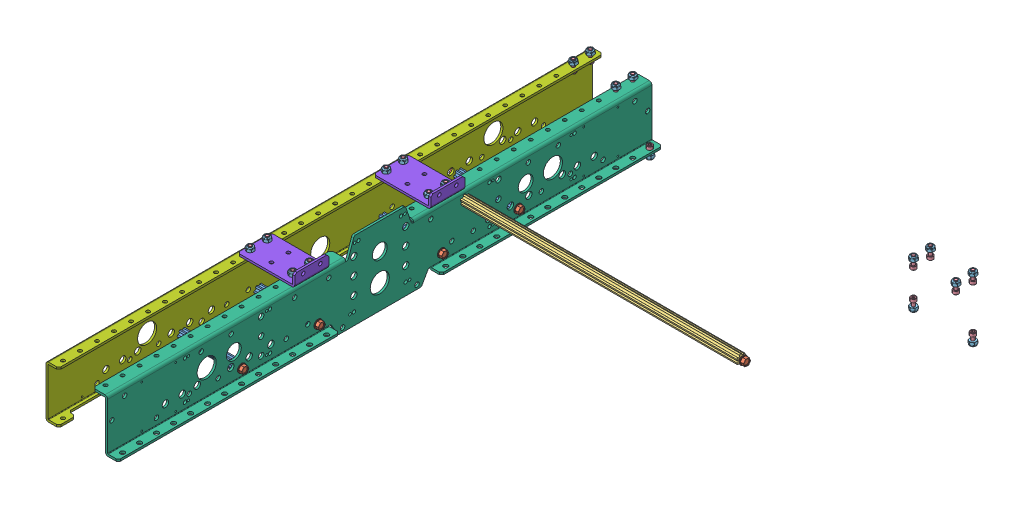
SolidWorks assembly AM14U3Long_Frame_Half, configuration Default. Lengths in mm.
Overall size (595.34 116.33 812.8).
59 component instances, 8 part files, 0 mates.
Components (placement in the parent):
- 500Churro_3.375-1: 500Churro_3.375 [Default] at (-501.65 -66.929 448.437) x (0 0 1) z (-1 0 0) size (14.66 12.7 85.72)
- 500Churro_3.375-2: 500Churro_3.375 [Default] at (-501.65 -66.929 562.737) x (0 0 1) z (-1 0 0) size (14.66 12.7 85.72)
- 500Churro_3.375-3: 500Churro_3.375 [Default] at (-501.65 -66.929 264.287) x (0 0 1) z (-1 0 0) size (14.66 12.7 85.72)
- 500Churro_3.375-4: 500Churro_3.375 [Default] at (-501.65 -66.929 149.987) x (0 0 1) z (-1 0 0) size (14.66 12.7 85.72)
- ThreadRollingScrew_0.25-20x0.75_FHTS 0.25-20-G-0.75-C-1: ThreadRollingScrew_0.25-20x0.75_FHTS 0.25-20-G-0.75-C [Default] at (-498.475 -66.929 562.737) x (-1 0 0) z (0 0.924225 0.381849) size (24.64 12.19 12.19)
- ThreadRollingScrew_0.25-20x0.75_FHTS 0.25-20-G-0.75-C-2: ThreadRollingScrew_0.25-20x0.75_FHTS 0.25-20-G-0.75-C [Default] at (-498.475 -66.929 448.437) x (-1 0 0) z (0 0.924225 0.381849) size (24.64 12.19 12.19)
- ThreadRollingScrew_0.25-20x0.75_FHTS 0.25-20-G-0.75-C-3: ThreadRollingScrew_0.25-20x0.75_FHTS 0.25-20-G-0.75-C [Default] at (-498.475 -66.929 264.287) x (-1 0 0) z (0 0.924225 0.381849) size (24.64 12.19 12.19)
- ThreadRollingScrew_0.25-20x0.75_FHTS 0.25-20-G-0.75-C-4: ThreadRollingScrew_0.25-20x0.75_FHTS 0.25-20-G-0.75-C [Default] at (-498.475 -66.929 149.987) x (-1 0 0) z (0 0.924225 0.381849) size (24.64 12.19 12.19)
- ThreadRollingScrew_0.25-20x0.75_FHTS 0.25-20-G-0.75-C-5: ThreadRollingScrew_0.25-20x0.75_FHTS 0.25-20-G-0.75-C [Default] at (-590.55 -66.929 562.737) size (24.64 12.19 12.19)
- ThreadRollingScrew_0.25-20x0.75_FHTS 0.25-20-G-0.75-C-6: ThreadRollingScrew_0.25-20x0.75_FHTS 0.25-20-G-0.75-C [Default] at (-590.55 -66.929 448.437) size (24.64 12.19 12.19)
- ThreadRollingScrew_0.25-20x0.75_FHTS 0.25-20-G-0.75-C-7: ThreadRollingScrew_0.25-20x0.75_FHTS 0.25-20-G-0.75-C [Default] at (-590.55 -66.929 149.987) size (24.64 12.19 12.19)
- ThreadRollingScrew_0.25-20x0.75_FHTS 0.25-20-G-0.75-C-8: ThreadRollingScrew_0.25-20x0.75_FHTS 0.25-20-G-0.75-C [Default] at (-590.55 -66.929 264.287) size (24.64 12.19 12.19)
- ThreadRollingScrew_0.25-20x0.75_FHTS 0.25-20-G-0.75-C-9: ThreadRollingScrew_0.25-20x0.75_FHTS 0.25-20-G-0.75-C [Default] at (-501.65 -15.494 229.362) size (24.64 12.19 12.19)
- ThreadRollingScrew_0.25-20x0.75_FHTS 0.25-20-G-0.75-C-10: ThreadRollingScrew_0.25-20x0.75_FHTS 0.25-20-G-0.75-C [Default] at (-82.55 -15.494 229.362) x (-1 0 0) z (0 -0.924225 -0.381849) size (24.64 12.19 12.19)
- 500Churro_cut_16.25-1: 500Churro_cut_16.25 [Default] at (-85.725 -15.494 229.362) x (0 0.99241 0.122972) z (-1 0 0) size (14.66 12.7 412.75)
- Screw_SHCS_10-32x0.5_HX-SHCS 0.19-32x1.375x1-C-1: Screw_SHCS_10-32x0.5_HX-SHCS 0.19-32x1.375x1-C [Default] at (-577.85 -11.43 -11.938) x (0 1 0) z (0 0 1) size (17.53 7.94 7.94)
- Screw_SHCS_10-32x0.5_HX-SHCS 0.19-32x1.375x1-C-2: Screw_SHCS_10-32x0.5_HX-SHCS 0.19-32x1.375x1-C [Default] at (-577.85 -11.43 -37.338) x (0 1 0) z (0 0 1) size (17.53 7.94 7.94)
- Screw_SHCS_10-32x0.5_HX-SHCS 0.19-32x1.375x1-C-3: Screw_SHCS_10-32x0.5_HX-SHCS 0.19-32x1.375x1-C [Default] at (-514.35 -11.43 -37.338) x (0 1 0) z (0 0 1) size (17.53 7.94 7.94)
- Screw_SHCS_10-32x0.5_HX-SHCS 0.19-32x1.375x1-C-4: Screw_SHCS_10-32x0.5_HX-SHCS 0.19-32x1.375x1-C [Default] at (-514.35 -11.43 -11.938) x (0 1 0) z (0 0 1) size (17.53 7.94 7.94)
- Screw_SHCS_10-32x0.5_HX-SHCS 0.19-32x1.375x1-C-5: Screw_SHCS_10-32x0.5_HX-SHCS 0.19-32x1.375x1-C [Default] at (-488.95 -73.152 -37.338) x (0 -1 0) z (0 0 1) size (17.53 7.94 7.94)
- Screw_SHCS_10-32x0.5_HX-SHCS 0.19-32x1.375x1-C-6: Screw_SHCS_10-32x0.5_HX-SHCS 0.19-32x1.375x1-C [Default] at (-577.85 -73.152 -37.338) x (0 -1 0) z (0 0 1) size (17.53 7.94 7.94)
- Screw_SHCS_10-32x0.5_HX-SHCS 0.19-32x1.375x1-C-7: Screw_SHCS_10-32x0.5_HX-SHCS 0.19-32x1.375x1-C [Default] at (-6.35 -11.176 -11.938) x (0 1 0) z (-0.991845 0 0.127447) size (17.53 7.94 7.94)
- Screw_SHCS_10-32x0.5_HX-SHCS 0.19-32x1.375x1-C-8: Screw_SHCS_10-32x0.5_HX-SHCS 0.19-32x1.375x1-C [Default] at (-6.35 -11.176 -37.338) x (0 1 0) z (0.595464 0 0.803382) size (17.53 7.94 7.94)
- Screw_SHCS_10-32x0.5_HX-SHCS 0.19-32x1.375x1-C-9: Screw_SHCS_10-32x0.5_HX-SHCS 0.19-32x1.375x1-C [Default] at (-69.85 -11.176 -11.938) x (0 1 0) z (0.578861 0 0.815426) size (17.53 7.94 7.94)
- Screw_SHCS_10-32x0.5_HX-SHCS 0.19-32x1.375x1-C-10: Screw_SHCS_10-32x0.5_HX-SHCS 0.19-32x1.375x1-C [Default] at (-69.85 -11.176 -37.338) x (0 1 0) z (0.958905 0 0.283727) size (17.53 7.94 7.94)
- Screw_SHCS_10-32x0.5_HX-SHCS 0.19-32x1.375x1-C-11: Screw_SHCS_10-32x0.5_HX-SHCS 0.19-32x1.375x1-C [Default] at (-6.35 -73.406 -37.338) x (0 -1 0) z (-0.989362 0 -0.145473) size (17.53 7.94 7.94)
- Screw_SHCS_10-32x0.5_HX-SHCS 0.19-32x1.375x1-C-12: Screw_SHCS_10-32x0.5_HX-SHCS 0.19-32x1.375x1-C [Default] at (-95.25 -73.406 -37.338) x (0 -1 0) z (-0.875347 0 0.483496) size (17.53 7.94 7.94)
- NylockNut_10-32-1: NylockNut_10-32 [Default] at (-69.85 0 -11.938) x (1 0 0) z (0 1 0) size (9.53 11 5.96)
- NylockNut_10-32-2: NylockNut_10-32 [Default] at (-69.85 0 -37.338) x (1 0 0) z (0 1 0) size (9.53 11 5.96)
- NylockNut_10-32-3: NylockNut_10-32 [Default] at (-6.35 0 -37.338) x (1 0 0) z (0 1 0) size (9.53 11 5.96)
- NylockNut_10-32-4: NylockNut_10-32 [Default] at (-6.35 0 -11.938) x (1 0 0) z (0 1 0) size (9.53 11 5.96)
- NylockNut_10-32-5: NylockNut_10-32 [Default] at (-6.35 -84.582 -37.338) x (1 0 0) z (0 -1 0) size (9.53 11 5.96)
- NylockNut_10-32-6: NylockNut_10-32 [Default] at (-95.25 -84.582 -37.338) x (1 0 0) z (0 -1 0) size (9.53 11 5.96)
- NylockNut_10-32-7: NylockNut_10-32 [Default] at (-514.35 0 -11.938) x (1 0 0) z (0 1 0) size (9.53 11 5.96)
- NylockNut_10-32-8: NylockNut_10-32 [Default] at (-514.35 0 -37.338) x (1 0 0) z (0 1 0) size (9.53 11 5.96)
- NylockNut_10-32-9: NylockNut_10-32 [Default] at (-577.85 0 -37.338) x (1 0 0) z (0 1 0) size (9.53 11 5.96)
- NylockNut_10-32-10: NylockNut_10-32 [Default] at (-577.85 0 -11.938) x (1 0 0) z (0 1 0) size (9.53 11 5.96)
- NylockNut_10-32-11: NylockNut_10-32 [Default] at (-488.95 -84.582 -37.338) x (1 0 0) z (0 -1 0) size (9.53 11 5.96)
- NylockNut_10-32-12: NylockNut_10-32 [Default] at (-577.85 -84.582 -37.338) x (1 0 0) z (0 -1 0) size (9.53 11 5.96)
- Screw_SHCS_10-32x0.5_HX-SHCS 0.19-32x1.375x1-C-13: Screw_SHCS_10-32x0.5_HX-SHCS 0.19-32x1.375x1-C [Default] at (-577.85 -11.43 445.262) x (0 1 0) z (0 0 1) size (17.53 7.94 7.94)
- Screw_SHCS_10-32x0.5_HX-SHCS 0.19-32x1.375x1-C-14: Screw_SHCS_10-32x0.5_HX-SHCS 0.19-32x1.375x1-C [Default] at (-577.85 -11.43 470.662) x (0 1 0) z (0 0 1) size (17.53 7.94 7.94)
- Screw_SHCS_10-32x0.5_HX-SHCS 0.19-32x1.375x1-C-15: Screw_SHCS_10-32x0.5_HX-SHCS 0.19-32x1.375x1-C [Default] at (-514.35 -11.43 445.262) x (0 1 0) z (0 0 1) size (17.53 7.94 7.94)
- Screw_SHCS_10-32x0.5_HX-SHCS 0.19-32x1.375x1-C-16: Screw_SHCS_10-32x0.5_HX-SHCS 0.19-32x1.375x1-C [Default] at (-514.35 -11.43 470.662) x (0 1 0) z (0 0 1) size (17.53 7.94 7.94)
- Screw_SHCS_10-32x0.5_HX-SHCS 0.19-32x1.375x1-C-17: Screw_SHCS_10-32x0.5_HX-SHCS 0.19-32x1.375x1-C [Default] at (-577.85 -11.43 267.462) x (0 1 0) z (0 0 1) size (17.53 7.94 7.94)
- Screw_SHCS_10-32x0.5_HX-SHCS 0.19-32x1.375x1-C-18: Screw_SHCS_10-32x0.5_HX-SHCS 0.19-32x1.375x1-C [Default] at (-577.85 -11.43 242.062) x (0 1 0) z (0 0 1) size (17.53 7.94 7.94)
- Screw_SHCS_10-32x0.5_HX-SHCS 0.19-32x1.375x1-C-19: Screw_SHCS_10-32x0.5_HX-SHCS 0.19-32x1.375x1-C [Default] at (-514.35 -11.43 242.062) x (0 1 0) z (0 0 1) size (17.53 7.94 7.94)
- Screw_SHCS_10-32x0.5_HX-SHCS 0.19-32x1.375x1-C-20: Screw_SHCS_10-32x0.5_HX-SHCS 0.19-32x1.375x1-C [Default] at (-514.35 -11.43 267.462) x (0 1 0) z (0 0 1) size (17.53 7.94 7.94)
- NylockNut_10-32-13: NylockNut_10-32 [Default] at (-514.35 -0.254 267.462) x (1 0 0) z (0 1 0) size (9.53 11 5.96)
- NylockNut_10-32-14: NylockNut_10-32 [Default] at (-514.35 -0.254 242.062) x (1 0 0) z (0 1 0) size (9.53 11 5.96)
- NylockNut_10-32-15: NylockNut_10-32 [Default] at (-577.85 -0.254 267.462) x (1 0 0) z (0 1 0) size (9.53 11 5.96)
- NylockNut_10-32-16: NylockNut_10-32 [Default] at (-577.85 -0.254 242.062) x (1 0 0) z (0 1 0) size (9.53 11 5.96)
- NylockNut_10-32-17: NylockNut_10-32 [Default] at (-514.35 -0.254 470.662) x (1 0 0) z (0 1 0) size (9.53 11 5.96)
- NylockNut_10-32-18: NylockNut_10-32 [Default] at (-577.85 -0.254 470.662) x (1 0 0) z (0 1 0) size (9.53 11 5.96)
- NylockNut_10-32-19: NylockNut_10-32 [Default] at (-577.85 -0.254 445.262) x (1 0 0) z (0 1 0) size (9.53 11 5.96)
- NylockNut_10-32-20: NylockNut_10-32 [Default] at (-514.35 -0.254 445.262) x (1 0 0) z (0 1 0) size (9.53 11 5.96)
- AM14U3InnerPlate_Long-1: AM14U3InnerPlate_Long [Default] at (-501.65 -77.216 762.762) x (0 0 -1) z (0 -1 0) size (812.8 38.1 116.33)
- AM14U3OuterPlate_Long_DefaultSM-FLAT-PATTERN-1: AM14U3OuterPlate_Long_DefaultSM-FLAT-PATTERN [Default] at (-587.375 -77.216 -50.038) x (0 0 1) z (0 -1 0) size (812.8 19.05 77.72)
- Bracket_2x3-1: Bracket_2x3 [Default] at (-584.2 -3.429 496.062) size (85.72 19.05 50.8)
- Bracket_2x3-2: Bracket_2x3 [Default] at (-584.2 -3.429 292.862) size (85.72 19.05 50.8)
